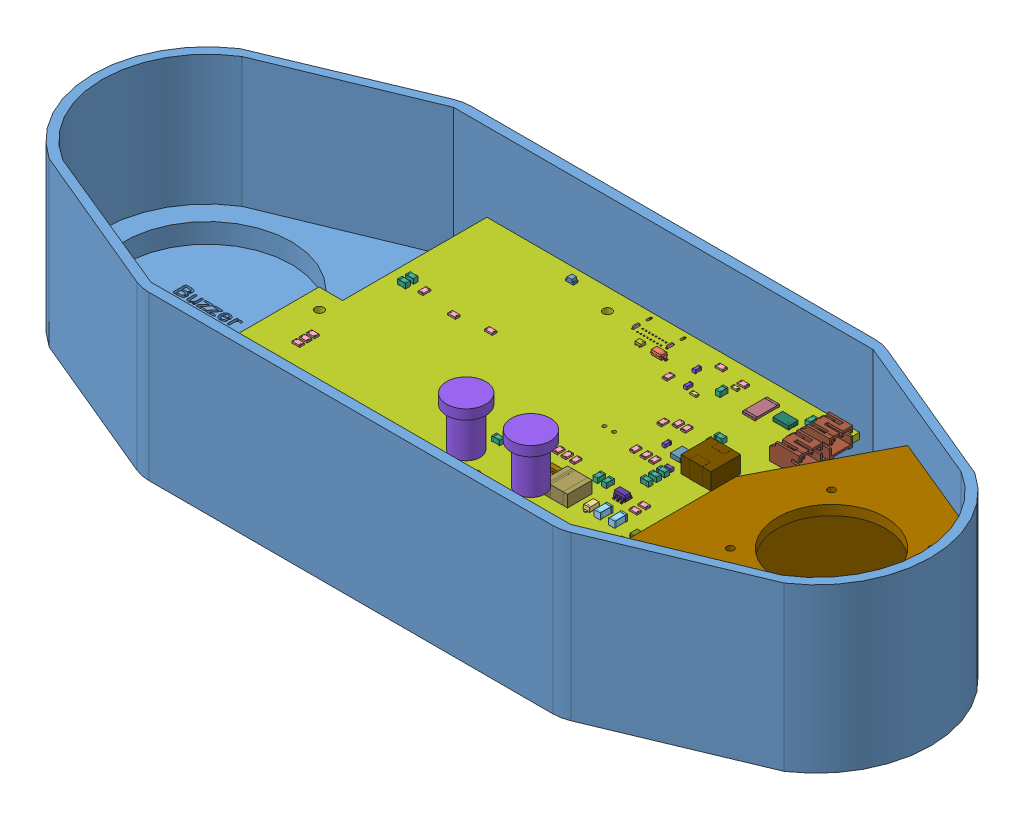
SolidWorks assembly BL, configuration Default. Lengths in mm.
Overall size (213.6 48.89 82.2).
228 component instances, 28 part files, 10 mates.
Components (placement in the parent):
- BL_Base-1: BL_Base [Default] at (-124.055 10.1413 263.066) size (213.6 41.6 82.2)
- BL_Top-1: BL_Top [Default] at (-124.055 48.2413 263.066) size (213.6 5 82.2) (hidden)
- BL_BatteryCover-1: BL_BatteryCover [Default] at (-42.555 23.6413 325.266) x (-1 0 0) z (0 0 1) size (61 14.5 48)
- boardlock.step-1: boardlock.step [Default] at (-123.5532 27.1413 339.7698) x (1 0 0) z (0 1 0) size (103.5 78.7 10.03)
  - R_0603_1608Metric.step-1: R_0603_1608Metric.step [Default] at (71.8174 63.3167 1.63) x (-1 0 0) z (0 0 1) size (1.6 0.8 0.45)
    - SOLID.step-1: SOLID.step [Default] at origin size (1.6 0.8 0.45)
  - R_0805_2012Metric.step-1: R_0805_2012Metric.step [Default] at (76.3532 54.7048 1.63) x (0 -1 0) z (0 0 1) size (2 1.2 0.45)
    - SOLID-0.step-1: SOLID-0.step [Default] at origin size (2 1.2 0.45)
  - R_0805_2012Metric.step-2: R_0805_2012Metric.step [Default] at (69.3682 72.6118 1.63) size (2 1.2 0.45)
    - SOLID-0.step-1: SOLID-0.step [Default] at origin size (2 1.2 0.45)
  - R_0805_2012Metric.step-3: R_0805_2012Metric.step [Default] at (5.3782 17.0013 1.63) x (0 -1 0) z (0 0 1) size (2 1.2 0.45)
    - SOLID-0.step-1: SOLID-0.step [Default] at origin size (2 1.2 0.45)
  - R_0805_2012Metric.step-4: R_0805_2012Metric.step [Default] at (66.9552 33.6228 1.63) x (0 -1 0) z (0 0 1) size (2 1.2 0.45)
    - SOLID-0.step-1: SOLID-0.step [Default] at origin size (2 1.2 0.45)
  - C_1206_3216Metric.step-1: C_1206_3216Metric.step [Default] at (90.3232 25.3093 1.63) x (0 1 0) z (0 0 1) size (3.2 1.6 1.6)
    - SOLID-1.step-1: SOLID-1.step [Default] at origin size (3.2 1.6 1.6)
  - C_0805_2012Metric.step-1: C_0805_2012Metric.step [Default] at (85.2951 56.4574 1.63) size (2 1.25 1.25)
    - SOLID-2.step-1: SOLID-2.step [Default] at origin size (2 1.25 1.25)
  - SOT-553.step-1: SOT-553.step [Default] at (53.671 67.6588 1.63) x (0 -1 0) z (0 0 1) size (1.6 1.6 0.63)
    - SOLID-3.step-1: SOLID-3.step [Default] at origin size (1.6 1.6 0.63)
  - C_0603_1608Metric.step-1: C_0603_1608Metric.step [Default] at (66.839 68.9301 1.63) x (0 1 0) z (0 0 1) size (1.6 0.8 0.8)
    - SOLID-4.step-1: SOLID-4.step [Default] at origin size (1.6 0.8 0.8)
  - SOT-23.step-1: SOT-23.step [Default] at (67.4378 28.4666 1.63) x (0 1 0) z (0 0 1) size (2.5 3 1.2)
    - SOLID-5.step-1: SOLID-5.step [Default] at origin size (2.5 3 1.2)
  - LGA-14_3x2.5mm_P0.5mm_LayoutBorder3x4y.step-1: LGA-14_3x2.5mm_P0.5mm_LayoutBorder3x4y.step [Default] at (6.6657 13.3713 1.63) size (3 2.5 0.78)
    - SOLID-6.step-1: SOLID-6.step [Default] at origin size (3 2.5 0.78)
  - C_0603_1608Metric.step-2: C_0603_1608Metric.step [Default] at (85.1416 43.5796 1.63) size (1.6 0.8 0.8)
    - SOLID-4.step-1: SOLID-4.step [Default] at origin size (1.6 0.8 0.8)
  - JST_PH_S2B-PH-K_1x02_P2.00mm_Horizontal.step-1: JST_PH_S2B-PH-K_1x02_P2.00mm_Horizontal.step [Default] at (97.195 60.3342 1.63) x (0 1 0) z (0 0 1) size (5.9 7.6 8.25)
    - SOLID-7.step-1: SOLID-7.step [Default] at origin size (5.9 7.6 8.25)
  - C_0805_2012Metric.step-2: C_0805_2012Metric.step [Default] at (85.3233 39.7188 1.63) size (2 1.25 1.25)
    - SOLID-2.step-1: SOLID-2.step [Default] at origin size (2 1.25 1.25)
  - C_0805_2012Metric.step-3: C_0805_2012Metric.step [Default] at (8.5352 9.7468 1.63) x (0 -1 0) z (0 0 1) size (2 1.25 1.25)
    - SOLID-2.step-1: SOLID-2.step [Default] at origin size (2 1.25 1.25)
  - R_0805_2012Metric.step-5: R_0805_2012Metric.step [Default] at (95.0222 21.9388 1.63) size (2 1.2 0.45)
    - SOLID-0.step-1: SOLID-0.step [Default] at origin size (2 1.2 0.45)
  - IND_EPCOS_B82462G4_EPC.step-1: IND_EPCOS_B82462G4_EPC.step [Default] at (77.3946 25.3601 1.63) size (6.3 6.31 3.01)
    - COMPOUND.step-1: COMPOUND.step [Default] at origin size (6.3 6.31 3.01)
  - SOT-23.step-2: SOT-23.step [Default] at (70.2382 23.7038 1.63) x (-1 0 0) z (0 0 1) size (2.5 3 1.2)
    - SOLID-5.step-1: SOLID-5.step [Default] at origin size (2.5 3 1.2)
  - R_2512_6332Metric.step-1: R_2512_6332Metric.step [Default] at (83.643 68.4482 1.63) x (0 -1 0) z (0 0 1) size (6.3 3.2 0.6)
    - SOLID-8.step-1: SOLID-8.step [Default] at origin size (6.3 3.2 0.6)
  - R_0805_2012Metric.step-6: R_0805_2012Metric.step [Default] at (14.6312 51.6568 1.63) x (0 -1 0) z (0 0 1) size (2 1.2 0.45)
    - SOLID-0.step-1: SOLID-0.step [Default] at origin size (2 1.2 0.45)
  - JST_PH_S2B-PH-K_1x02_P2.00mm_Horizontal.step-2: JST_PH_S2B-PH-K_1x02_P2.00mm_Horizontal.step [Default] at (97.2458 68.0558 1.63) x (0 1 0) z (0 0 1) size (5.9 7.6 8.25)
    - SOLID-7.step-1: SOLID-7.step [Default] at origin size (5.9 7.6 8.25)
  - TPS630701RNMR.step-1: TPS630701RNMR.step [Default] at (83.7446 47.9992 1.63) size (2.5 3 1)
    - COMPOUND-9.step-1: COMPOUND-9.step [Default] at origin size (2.5 3 1)
  - R_0805_2012Metric.step-7: R_0805_2012Metric.step [Default] at (78.5122 54.7048 1.63) x (0 -1 0) z (0 0 1) size (2 1.2 0.45)
    - SOLID-0.step-1: SOLID-0.step [Default] at origin size (2 1.2 0.45)
  - R_0805_2012Metric.step-8: R_0805_2012Metric.step [Default] at (9.9482 25.9938 1.63) size (2 1.2 0.45)
    - SOLID-0.step-1: SOLID-0.step [Default] at origin size (2 1.2 0.45)
  - R_0805_2012Metric.step-9: R_0805_2012Metric.step [Default] at (31.8882 51.2758 1.63) size (2 1.2 0.45)
    - SOLID-0.step-1: SOLID-0.step [Default] at origin size (2 1.2 0.45)
  - R_0805_2012Metric.step-10: R_0805_2012Metric.step [Default] at (75.9322 71.6987 1.63) size (2 1.2 0.45)
    - SOLID-0.step-1: SOLID-0.step [Default] at origin size (2 1.2 0.45)
  - R_0805_2012Metric.step-11: R_0805_2012Metric.step [Default] at (64.6692 63.8488 1.63) x (0 1 0) z (0 0 1) size (2 1.2 0.45)
    - SOLID-0.step-1: SOLID-0.step [Default] at origin size (2 1.2 0.45)
  - Texas_S-PDSO-N12.step-1: Texas_S-PDSO-N12.step [Default] at (89.5462 68.8223 1.63) x (-1 0 0) z (0 0 1) size (4 2.5 0.92)
    - SOLID-10.step-1: SOLID-10.step [Default] at origin size (4 2.5 0.92)
  - C_0603_1608Metric.step-3: C_0603_1608Metric.step [Default] at (85.1173 52.6474 1.63) size (1.6 0.8 0.8)
    - SOLID-4.step-1: SOLID-4.step [Default] at origin size (1.6 0.8 0.8)
  - R_0805_2012Metric.step-12: R_0805_2012Metric.step [Default] at (69.1142 33.6228 1.63) x (0 -1 0) z (0 0 1) size (2 1.2 0.45)
    - SOLID-0.step-1: SOLID-0.step [Default] at origin size (2 1.2 0.45)
  - R_0603_1608Metric.step-2: R_0603_1608Metric.step [Default] at (75.729 69.8699 1.63) size (1.6 0.8 0.45)
    - SOLID.step-1: SOLID.step [Default] at origin size (1.6 0.8 0.45)
  - SOT-323_SC-70.step-1: SOT-323_SC-70.step [Default] at (95.6572 24.4788 1.63) x (-1 0 0) z (0 0 1) size (2 2 1.05)
    - SOLID-11.step-1: SOLID-11.step [Default] at origin size (2 2 1.05)
  - SOT-23-5.step-1: SOT-23-5.step [Default] at (85.3956 31.3838 1.63) x (0 1 0) z (0 0 1) size (2.8 2.9 1.55)
    - SOLID-12.step-1: SOLID-12.step [Default] at origin size (2.8 2.9 1.55)
  - R_0805_2012Metric.step-13: R_0805_2012Metric.step [Default] at (74.0672 53.0538 1.63) x (0 -1 0) z (0 0 1) size (2 1.2 0.45)
    - SOLID-0.step-1: SOLID-0.step [Default] at origin size (2 1.2 0.45)
  - C_1206_3216Metric.step-2: C_1206_3216Metric.step [Default] at (86.6148 25.3093 1.63) x (0 1 0) z (0 0 1) size (3.2 1.6 1.6)
    - SOLID-1.step-1: SOLID-1.step [Default] at origin size (3.2 1.6 1.6)
  - R_0805_2012Metric.step-14: R_0805_2012Metric.step [Default] at (7.2782 17.0013 1.63) x (0 -1 0) z (0 0 1) size (2 1.2 0.45)
    - SOLID-0.step-1: SOLID-0.step [Default] at origin size (2 1.2 0.45)
  - C_0805_2012Metric.step-4: C_0805_2012Metric.step [Default] at (78.436 32.3998 1.63) x (0 -1 0) z (0 0 1) size (2 1.25 1.25)
    - SOLID-2.step-1: SOLID-2.step [Default] at origin size (2 1.25 1.25)
  - C_0805_2012Metric.step-5: C_0805_2012Metric.step [Default] at (75.0686 67.0036 1.63) x (0 -1 0) z (0 0 1) size (2 1.25 1.25)
    - SOLID-2.step-1: SOLID-2.step [Default] at origin size (2 1.25 1.25)
  - R_0805_2012Metric.step-15: R_0805_2012Metric.step [Default] at (90.0184 32.3197 1.63) x (-1 0 0) z (0 0 1) size (2 1.2 0.45)
    - SOLID-0.step-1: SOLID-0.step [Default] at origin size (2 1.2 0.45)
  - C_0805_2012Metric.step-6: C_0805_2012Metric.step [Default] at (57.1757 27.8838 1.63) x (-1 0 0) z (0 0 1) size (2 1.25 1.25)
    - SOLID-2.step-1: SOLID-2.step [Default] at origin size (2 1.25 1.25)
  - C_0805_2012Metric.step-7: C_0805_2012Metric.step [Default] at (85.2951 54.4254 1.63) size (2 1.25 1.25)
    - SOLID-2.step-1: SOLID-2.step [Default] at origin size (2 1.25 1.25)
  - DR74.step-1: DR74.step [Default] at (91.3392 47.9992 1.63) x (0 -1 0) z (0 0 1) size (7.62 7.62 4.34)
    - COMPOUND-13.step-1: COMPOUND-13.step [Default] at origin size (7.62 7.62 4.34)
  - C_0805_2012Metric.step-8: C_0805_2012Metric.step [Default] at (85.3194 37.6614 1.63) size (2 1.25 1.25)
    - SOLID-2.step-1: SOLID-2.step [Default] at origin size (2 1.25 1.25)
  - C_0805_2012Metric.step-9: C_0805_2012Metric.step [Default] at (80.6712 32.3998 1.63) x (0 -1 0) z (0 0 1) size (2 1.25 1.25)
    - SOLID-2.step-1: SOLID-2.step [Default] at origin size (2 1.25 1.25)
  - R_0805_2012Metric.step-16: R_0805_2012Metric.step [Default] at (23.6482 50.1328 1.63) size (2 1.2 0.45)
    - SOLID-0.step-1: SOLID-0.step [Default] at origin size (2 1.2 0.45)
  - C_0805_2012Metric.step-10: C_0805_2012Metric.step [Default] at (10.5181 50.5096 1.63) x (-1 0 0) z (0 0 1) size (2 1.25 1.25)
    - SOLID-2.step-1: SOLID-2.step [Default] at origin size (2 1.25 1.25)
  - R_0805_2012Metric.step-17: R_0805_2012Metric.step [Default] at (79.1776 43.7066 1.63) x (0 1 0) z (0 0 1) size (2 1.2 0.45)
    - SOLID-0.step-1: SOLID-0.step [Default] at origin size (2 1.2 0.45)
  - SOT-23.step-3: SOT-23.step [Default] at (71.197 28.4158 1.63) x (0 1 0) z (0 0 1) size (2.5 3 1.2)
    - SOLID-5.step-1: SOLID-5.step [Default] at origin size (2.5 3 1.2)
  - C_0805_2012Metric.step-11: C_0805_2012Metric.step [Default] at (30.3382 3.3213 1.63) x (0 1 0) z (0 0 1) size (2 1.25 1.25)
    - SOLID-2.step-1: SOLID-2.step [Default] at origin size (2 1.25 1.25)
  - C_0805_2012Metric.step-12: C_0805_2012Metric.step [Default] at (85.3233 41.7762 1.63) size (2 1.25 1.25)
    - SOLID-2.step-1: SOLID-2.step [Default] at origin size (2 1.25 1.25)
  - SOT-23.step-4: SOT-23.step [Default] at (95.2766 19.0185 1.63) x (-1 0 0) z (0 0 1) size (2.5 3 1.2)
    - SOLID-5.step-1: SOLID-5.step [Default] at origin size (2.5 3 1.2)
  - LED_0805_2012Metric.step-1: LED_0805_2012Metric.step [Default] at (31.1157 72.7438 1.63) x (-1 0 0) z (0 0 1) size (2 1.25 1.1)
    - SOLID-14.step-1: SOLID-14.step [Default] at origin size (2 1.25 1.1)
  - D_SOD-123.step-1: D_SOD-123.step [Default] at (58.7424 67.3794 1.63) x (-1 0 0) z (0 0 1) size (3.8 1.6 1.25)
    - SOLID-15.step-1: SOLID-15.step [Default] at origin size (3.8 1.6 1.25)
  - D_SOD-123F.step-1: D_SOD-123F.step [Default] at (83.5922 25.2585 1.63) x (0 1 0) z (0 0 1) size (3.5 1.6 1.1)
    - SOLID-16.step-1: SOLID-16.step [Default] at origin size (3.5 1.6 1.1)
  - C_0805_2012Metric.step-13: C_0805_2012Metric.step [Default] at (10.5181 52.5416 1.63) x (-1 0 0) z (0 0 1) size (2 1.25 1.25)
    - SOLID-2.step-1: SOLID-2.step [Default] at origin size (2 1.25 1.25)
  - R_0805_2012Metric.step-18: R_0805_2012Metric.step [Default] at (9.9782 24.0638 1.63) size (2 1.2 0.45)
    - SOLID-0.step-1: SOLID-0.step [Default] at origin size (2 1.2 0.45)
  - C_0805_2012Metric.step-14: C_0805_2012Metric.step [Default] at (57.1382 22.3838 1.63) x (-1 0 0) z (0 0 1) size (2 1.25 1.25)
    - SOLID-2.step-1: SOLID-2.step [Default] at origin size (2 1.25 1.25)
  - R_0805_2012Metric.step-19: R_0805_2012Metric.step [Default] at (71.2732 33.6228 1.63) x (0 -1 0) z (0 0 1) size (2 1.2 0.45)
    - SOLID-0.step-1: SOLID-0.step [Default] at origin size (2 1.2 0.45)
  - R_0805_2012Metric.step-20: R_0805_2012Metric.step [Default] at (76.4802 43.6558 1.63) x (0 1 0) z (0 0 1) size (2 1.2 0.45)
    - SOLID-0.step-1: SOLID-0.step [Default] at origin size (2 1.2 0.45)
  - R_0805_2012Metric.step-21: R_0805_2012Metric.step [Default] at (90.0184 30.0337 1.63) size (2 1.2 0.45)
    - SOLID-0.step-1: SOLID-0.step [Default] at origin size (2 1.2 0.45)
  - C_0805_2012Metric.step-15: C_0805_2012Metric.step [Default] at (5.2332 9.7468 1.63) x (0 -1 0) z (0 0 1) size (2 1.25 1.25)
    - SOLID-2.step-1: SOLID-2.step [Default] at origin size (2 1.25 1.25)
  - C_0805_2012Metric.step-16: C_0805_2012Metric.step [Default] at (93.1934 71.799 1.63) x (0 1 0) z (0 0 1) size (2 1.25 1.25)
    - SOLID-2.step-1: SOLID-2.step [Default] at origin size (2 1.25 1.25)
  - R_0805_2012Metric.step-22: R_0805_2012Metric.step [Default] at (9.9582 27.8938 1.63) size (2 1.2 0.45)
    - SOLID-0.step-1: SOLID-0.step [Default] at origin size (2 1.2 0.45)
  - C_0603_1608Metric.step-4: C_0603_1608Metric.step [Default] at (79.4316 48.6331 1.63) x (0 1 0) z (0 0 1) size (1.6 0.8 0.8)
    - SOLID-4.step-1: SOLID-4.step [Default] at origin size (1.6 0.8 0.8)
  - R_0805_2012Metric.step-23: R_0805_2012Metric.step [Default] at (81.3366 43.7066 1.63) x (0 1 0) z (0 0 1) size (2 1.2 0.45)
    - SOLID-0.step-1: SOLID-0.step [Default] at origin size (2 1.2 0.45)
  - C_0603_1608Metric.step-5: C_0603_1608Metric.step [Default] at (69.3536 64.2311 1.63) x (0 -1 0) z (0 0 1) size (1.6 0.8 0.8)
    - SOLID-4.step-1: SOLID-4.step [Default] at origin size (1.6 0.8 0.8)
  - R_0805_2012Metric.step-24: R_0805_2012Metric.step [Default] at (8.9982 30.4338 -0.05) x (0 -1 0) z (0 0 -1) size (2 1.2 0.45)
    - SOLID-0.step-1: SOLID-0.step [Default] at origin size (2 1.2 0.45)
  - C_0805_2012Metric.step-17: C_0805_2012Metric.step [Default] at (71.4322 6.1908 -0.05) x (-1 0 0) z (0 0 -1) size (2 1.25 1.25)
    - SOLID-2.step-1: SOLID-2.step [Default] at origin size (2 1.25 1.25)
  - R_0805_2012Metric.step-25: R_0805_2012Metric.step [Default] at (50.0134 67.6588 -0.05) x (-1 0 0) z (0 0 -1) size (2 1.2 0.45)
    - SOLID-0.step-1: SOLID-0.step [Default] at origin size (2 1.2 0.45)
  - C_0805_2012Metric.step-18: C_0805_2012Metric.step [Default] at (72.6702 50.2598 -0.05) x (-1 0 0) z (0 0 -1) size (2 1.25 1.25)
    - SOLID-2.step-1: SOLID-2.step [Default] at origin size (2 1.25 1.25)
  - R_0805_2012Metric.step-26: R_0805_2012Metric.step [Default] at (6.9982 30.3938 -0.05) x (0 -1 0) z (0 0 -1) size (2 1.2 0.45)
    - SOLID-0.step-1: SOLID-0.step [Default] at origin size (2 1.2 0.45)
  - C_0805_2012Metric.step-19: C_0805_2012Metric.step [Default] at (89.4257 18.2938 -0.05) x (1 0 0) z (0 0 -1) size (2 1.25 1.25)
    - SOLID-2.step-1: SOLID-2.step [Default] at origin size (2 1.25 1.25)
  - R_0805_2012Metric.step-27: R_0805_2012Metric.step [Default] at (89.4857 20.2438 -0.05) x (-1 0 0) z (0 0 -1) size (2 1.2 0.45)
    - SOLID-0.step-1: SOLID-0.step [Default] at origin size (2 1.2 0.45)
  - R_0805_2012Metric.step-28: R_0805_2012Metric.step [Default] at (89.5257 22.1438 -0.05) x (-1 0 0) z (0 0 -1) size (2 1.2 0.45)
    - SOLID-0.step-1: SOLID-0.step [Default] at origin size (2 1.2 0.45)
  - R_0805_2012Metric.step-29: R_0805_2012Metric.step [Default] at (56.7952 59.1498 -0.05) x (0 1 0) z (0 0 -1) size (2 1.2 0.45)
    - SOLID-0.step-1: SOLID-0.step [Default] at origin size (2 1.2 0.45)
  - C_0805_2012Metric.step-20: C_0805_2012Metric.step [Default] at (64.2882 54.7048 -0.05) x (1 0 0) z (0 0 -1) size (2 1.25 1.25)
    - SOLID-2.step-1: SOLID-2.step [Default] at origin size (2 1.25 1.25)
  - C_0805_2012Metric.step-21: C_0805_2012Metric.step [Default] at (94.4126 67.989 -0.05) x (0 -1 0) z (0 0 -1) size (2 1.25 1.25)
    - SOLID-2.step-1: SOLID-2.step [Default] at origin size (2 1.25 1.25)
  - R_0805_2012Metric.step-30: R_0805_2012Metric.step [Default] at (61.2642 55.5242 -0.05) x (0 1 0) z (0 0 -1) size (2 1.2 0.45)
    - SOLID-0.step-1: SOLID-0.step [Default] at origin size (2 1.2 0.45)
  - C_0603_1608Metric.step-6: C_0603_1608Metric.step [Default] at (64.0582 56.6672 -0.05) x (1 0 0) z (0 0 -1) size (1.6 0.8 0.8)
    - SOLID-4.step-1: SOLID-4.step [Default] at origin size (1.6 0.8 0.8)
  - R_0805_2012Metric.step-31: R_0805_2012Metric.step [Default] at (29.0682 72.7138 -0.05) x (1 0 0) z (0 0 -1) size (2 1.2 0.45)
    - SOLID-0.step-1: SOLID-0.step [Default] at origin size (2 1.2 0.45)
  - R_0603_1608Metric.step-3: R_0603_1608Metric.step [Default] at (66.8282 68.9288 -0.05) x (0 1 0) z (0 0 -1) size (1.6 0.8 0.45)
    - SOLID.step-1: SOLID.step [Default] at origin size (1.6 0.8 0.45)
  - C_0805_2012Metric.step-22: C_0805_2012Metric.step [Default] at (68.2092 47.7772 -0.05) x (-1 0 0) z (0 0 -1) size (2 1.25 1.25)
    - SOLID-2.step-1: SOLID-2.step [Default] at origin size (2 1.25 1.25)
  - USB_C_Receptacle_GCT_USB4085.step-1: USB_C_Receptacle_GCT_USB4085.step [Default] at (53.5154 74.4415 -0.05) x (1 0 0) z (0 1 0) size (9.05 5.6 9.18)
    - COMPOUND-17.step-1: COMPOUND-17.step [Default] at origin size (9.05 5.6 9.18)
  - R_0805_2012Metric.step-32: R_0805_2012Metric.step [Default] at (76.3532 54.7208 -0.05) x (0 -1 0) z (0 0 -1) size (2 1.2 0.45)
    - SOLID-0.step-1: SOLID-0.step [Default] at origin size (2 1.2 0.45)
  - L_1210_3225Metric.step-1: L_1210_3225Metric.step [Default] at (68.6062 54.4508 -0.05) x (0 1 0) z (0 0 -1) size (3.2 2.5 2.5)
    - SOLID-18.step-1: SOLID-18.step [Default] at origin size (3.2 2.5 2.5)
  - C_0805_2012Metric.step-23: C_0805_2012Metric.step [Default] at (64.2882 52.4508 -0.05) x (1 0 0) z (0 0 -1) size (2 1.25 1.25)
    - SOLID-2.step-1: SOLID-2.step [Default] at origin size (2 1.25 1.25)
  - L_1210_3225Metric.step-2: L_1210_3225Metric.step [Default] at (72.5432 54.4508 -0.05) x (0 1 0) z (0 0 -1) size (3.2 2.5 2.5)
    - SOLID-18.step-1: SOLID-18.step [Default] at origin size (3.2 2.5 2.5)
  - 503398-1892.step-1: 503398-1892.step [Default] at (91.1106 9.5182 -0.05) x (0 1 0) z (-1 0 0) size (13.1 1.44 14.07)
    - COMPOUND-19.step-1: COMPOUND-19.step [Default] at origin size (13.1 1.44 14.07)
  - C_0805_2012Metric.step-24: C_0805_2012Metric.step [Default] at (58.6098 66.3132 -0.05) x (0 1 0) z (0 0 -1) size (2 1.25 1.25)
    - SOLID-2.step-1: SOLID-2.step [Default] at origin size (2 1.25 1.25)
  - R_0805_2012Metric.step-33: R_0805_2012Metric.step [Default] at (86.5132 70.5798 -0.05) x (0 -1 0) z (0 0 -1) size (2 1.2 0.45)
    - SOLID-0.step-1: SOLID-0.step [Default] at origin size (2 1.2 0.45)
  - R_0805_2012Metric.step-34: R_0805_2012Metric.step [Default] at (69.4044 72.5369 -0.05) x (1 0 0) z (0 0 -1) size (2 1.2 0.45)
    - SOLID-0.step-1: SOLID-0.step [Default] at origin size (2 1.2 0.45)
  - R_0805_2012Metric.step-35: R_0805_2012Metric.step [Default] at (81.3062 21.6086 -0.05) x (0 -1 0) z (0 0 -1) size (2 1.2 0.45)
    - SOLID-0.step-1: SOLID-0.step [Default] at origin size (2 1.2 0.45)
  - R_0805_2012Metric.step-36: R_0805_2012Metric.step [Default] at (7.3682 21.5638 -0.05) x (-1 0 0) z (0 0 -1) size (2 1.2 0.45)
    - SOLID-0.step-1: SOLID-0.step [Default] at origin size (2 1.2 0.45)
  - SOT-323_SC-70.step-2: SOT-323_SC-70.step [Default] at (7.6582 23.8138 -0.05) x (-1 0 0) z (0 0 -1) size (2 2 1.05)
    - SOLID-11.step-1: SOLID-11.step [Default] at origin size (2 2 1.05)
  - C_0805_2012Metric.step-25: C_0805_2012Metric.step [Default] at (84.3882 21.5538 -0.05) x (1 0 0) z (0 0 -1) size (2 1.25 1.25)
    - SOLID-2.step-1: SOLID-2.step [Default] at origin size (2 1.25 1.25)
  - SOT-23.step-5: SOT-23.step [Default] at (7.8657 26.8438 -0.05) x (-1 0 0) z (0 0 -1) size (2.5 3 1.2)
    - SOLID-5.step-1: SOLID-5.step [Default] at origin size (2.5 3 1.2)
  - R_0805_2012Metric.step-37: R_0805_2012Metric.step [Default] at (35.8882 71.9238 -0.05) x (1 0 0) z (0 0 -1) size (2 1.2 0.45)
    - SOLID-0.step-1: SOLID-0.step [Default] at origin size (2 1.2 0.45)
  - C_0805_2012Metric.step-26: C_0805_2012Metric.step [Default] at (68.6062 50.2598 -0.05) x (1 0 0) z (0 0 -1) size (2 1.25 1.25)
    - SOLID-2.step-1: SOLID-2.step [Default] at origin size (2 1.25 1.25)
  - R_0805_2012Metric.step-38: R_0805_2012Metric.step [Default] at (71.4322 10.5088 -0.05) x (1 0 0) z (0 0 -1) size (2 1.2 0.45)
    - SOLID-0.step-1: SOLID-0.step [Default] at origin size (2 1.2 0.45)
  - R_0805_2012Metric.step-39: R_0805_2012Metric.step [Default] at (66.5902 8.3498 -0.05) x (-1 0 0) z (0 0 -1) size (2 1.2 0.45)
    - SOLID-0.step-1: SOLID-0.step [Default] at origin size (2 1.2 0.45)
  - R_0805_2012Metric.step-40: R_0805_2012Metric.step [Default] at (71.4322 8.3498 -0.05) x (1 0 0) z (0 0 -1) size (2 1.2 0.45)
    - SOLID-0.step-1: SOLID-0.step [Default] at origin size (2 1.2 0.45)
  - R_0805_2012Metric.step-41: R_0805_2012Metric.step [Default] at (73.8682 20.4738 -0.05) x (0 -1 0) z (0 0 -1) size (2 1.2 0.45)
    - SOLID-0.step-1: SOLID-0.step [Default] at origin size (2 1.2 0.45)
  - R_0805_2012Metric.step-42: R_0805_2012Metric.step [Default] at (66.5902 10.5088 -0.05) x (-1 0 0) z (0 0 -1) size (2 1.2 0.45)
    - SOLID-0.step-1: SOLID-0.step [Default] at origin size (2 1.2 0.45)
  - C_0805_2012Metric.step-27: C_0805_2012Metric.step [Default] at (77.1707 20.8638 -0.05) x (1 0 0) z (0 0 -1) size (2 1.25 1.25)
    - SOLID-2.step-1: SOLID-2.step [Default] at origin size (2 1.25 1.25)
  - C_0805_2012Metric.step-28: C_0805_2012Metric.step [Default] at (66.5902 6.1908 -0.05) x (1 0 0) z (0 0 -1) size (2 1.25 1.25)
    - SOLID-2.step-1: SOLID-2.step [Default] at origin size (2 1.25 1.25)
  - R_0603_1608Metric.step-4: R_0603_1608Metric.step [Default] at (71.8174 63.3167 -0.05) x (1 0 0) z (0 0 -1) size (1.6 0.8 0.45)
    - SOLID.step-1: SOLID.step [Default] at origin size (1.6 0.8 0.45)
  - R_0805_2012Metric.step-43: R_0805_2012Metric.step [Default] at (60.337 70.8344 -0.05) x (0 1 0) z (0 0 -1) size (2 1.2 0.45)
    - SOLID-0.step-1: SOLID-0.step [Default] at origin size (2 1.2 0.45)
  - R_0805_2012Metric.step-44: R_0805_2012Metric.step [Default] at (77.3038 65.3487 -0.05) x (0 -1 0) z (0 0 -1) size (2 1.2 0.45)
    - SOLID-0.step-1: SOLID-0.step [Default] at origin size (2 1.2 0.45)
  - R_0805_2012Metric.step-45: R_0805_2012Metric.step [Default] at (58.9542 59.1338 -0.05) x (0 1 0) z (0 0 -1) size (2 1.2 0.45)
    - SOLID-0.step-1: SOLID-0.step [Default] at origin size (2 1.2 0.45)
  - R_0805_2012Metric.step-46: R_0805_2012Metric.step [Default] at (11.0182 24.8238 -0.05) x (0 1 0) z (0 0 -1) size (2 1.2 0.45)
    - SOLID-0.step-1: SOLID-0.step [Default] at origin size (2 1.2 0.45)
  - boardlock PCB.step-1: boardlock PCB.step [Default] at origin size (101 76.2 1.58)
- BL_ButtonExtender-1: BL_ButtonExtender [Default] at (-38.225 43.0354 331.666) size (10 12.5 10)
- BL_ButtonExtender-2: BL_ButtonExtender [Default] at (-54.735 42.8845 331.666) size (10 12.5 10)
- Speaker_Holder-2: Speaker_Holder [Default] at (-124.055 35.1413 263.066) size (50.98 28.5 77.2)
Mates (geometry in assembly coordinates):
- Coincident2: coincident anti-aligned: line of BL_Base-1 through (-103.555 9.1413 325.266) axis (1 0 0); line of BL_BatteryCover-1 through (-73.055 9.1413 325.266) axis (-1 0 0)
- Coincident3: coincident anti-aligned: line of BL_Base-1 through (-103.555 9.1413 277.266) axis (0 0 1); line of BL_BatteryCover-1 through (-103.555 9.1413 282.266) axis (0 0 -1)
- Concentric2: concentric aligned: circle of BL_Base-1; circle of boardlock.step-1/boardlock PCB.step-1
- Coincident4: coincident anti-aligned: plane of BL_Base-1 through (-81.441 27.1413 268.936) normal (0 1 0); plane of boardlock.step-1/boardlock PCB.step-1 through (-72.4302 27.1413 302.2929) normal (0 -1 0)
- Coincident5: coincident anti-aligned: line of BL_Base-1 through (-19.555 48.2413 263.066) axis (-1 0 0); line of BL_Top-1 through (-126.555 48.2413 263.066) axis (1 0 0)
- Coincident8: coincident anti-aligned: circle of BL_Base-1; circle of BL_Top-1
- Concentric6: concentric aligned: circle of BL_Top-1; circle of BL_ButtonExtender-1
- Concentric8: concentric aligned: circle of BL_Top-1; circle of BL_ButtonExtender-2
- Coincident11: coincident: plane of BL_Base-1 through (-124.055 9.1413 263.066) normal (0 1 0); plane of Speaker_Holder-2 through (-125.0121 9.1413 264.548) normal (0 -1 0)
- Coincident12: coincident: point of BL_Base-1; point of Speaker_Holder-2
